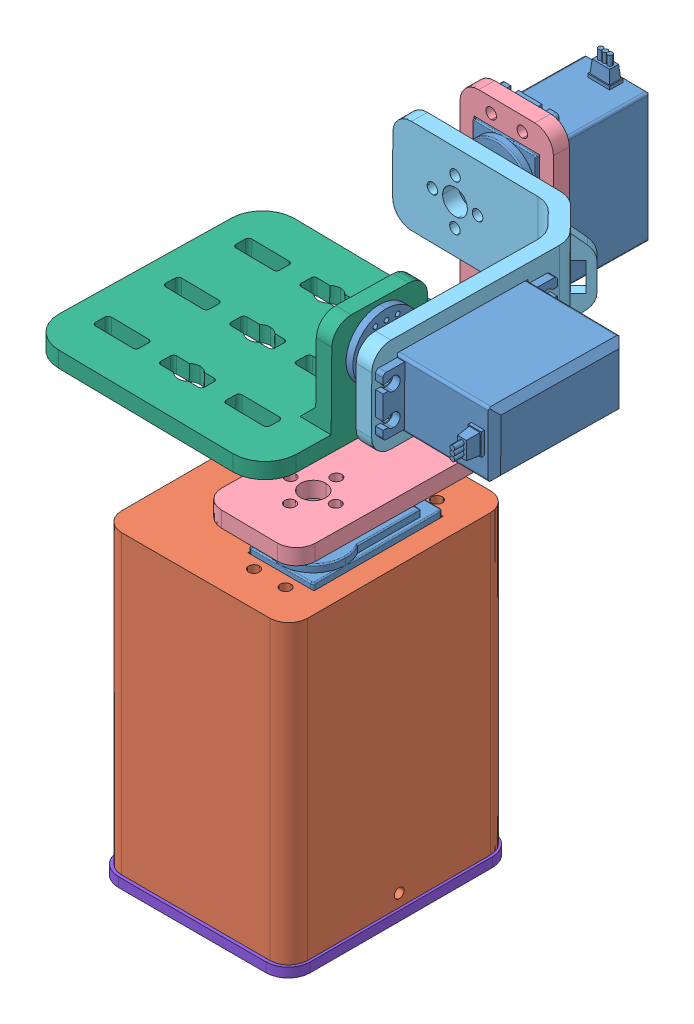
SolidWorks assembly DIY Arduino Gimbal - Self-Stabilizing Platform 3D Model, configuration Default. Lengths in mm.
Overall size (124.4 189.81 139.25).
11 component instances, 8 part files, 0 mates.
Components (placement in the parent):
- DIY Arduino Gimbal - Self-Stabilizing Platform 3D Model.STEP-1: DIY Arduino Gimbal - Self-Stabilizing Platform 3D Model.STEP [Default] at origin size (124.4 189.81 139.25)
  - Servo MG996R_r1.STEP-1: Servo MG996R_r1.STEP [Default] at (83.1717 161.9698 199.6218) x (0 0 -1) z (1 0 0) size (55.8 47.4 21)
  - Base 01 - Yaw servo.STEP-1: Base 01 - Yaw servo.STEP [Default] at (83.1717 193.1698 199.6218) x (-1 0 0) z (0 0 -1) size (59 94 70)
  - MPU6050 model.STEP-1: MPU6050 model.STEP [Default] at (62.8717 197.1698 199.1218) x (0 0 -1) z (1 0 0) size (20 11.2 15)
  - Base 02 - Roll servo.STEP-1: Base 02 - Roll servo.STEP [Default] at (97.9184 214.3698 230.0593) x (-0.012607 0 0.999921) z (0 -1 0) size (85.61 30 80.61)
  - Servo MG996R_r1.STEP-2: Servo MG996R_r1.STEP [Default] at (84.3921 261.4764 113.0729) x (0 -1 0) z (-0.999921 0 -0.012607) size (55.8 47.4 21)
  - Base 03 - Pitch servo.STEP-1: Base 03 - Pitch servo.STEP [Default] at (63.6981 256.7732 165.2161) x (-0.999918 0.002335 -0.012606) z (0.012607 0 -0.999921) size (63.49 30 73.49)
  - Servo MG996R_r1.STEP-3: Servo MG996R_r1.STEP [Default] at (157.9066 271.5521 206.3923) x (0.012607 0 -0.999921) z (0.002335 0.999997 0.000029) size (55.8 47.4 21)
  - Top platform.STEP-1: Top platform.STEP [Default] at (110.374 268.6628 216.0637) x (0.012591 -0.006618 -0.999899) z (0.002418 0.999975 -0.006588) size (74 76 35)
  - battery holder.STEP-1: battery holder.STEP [Default] at (44.1717 150.362 208.17) x (0 -1 0) z (0 0 1) size (75 23 40)
  - bottom cover.STEP-1: bottom cover.STEP [Default] at (70.5717 103.1698 199.7218) x (0 0 -1) z (1 0 0) size (71.8 11 60.8)
